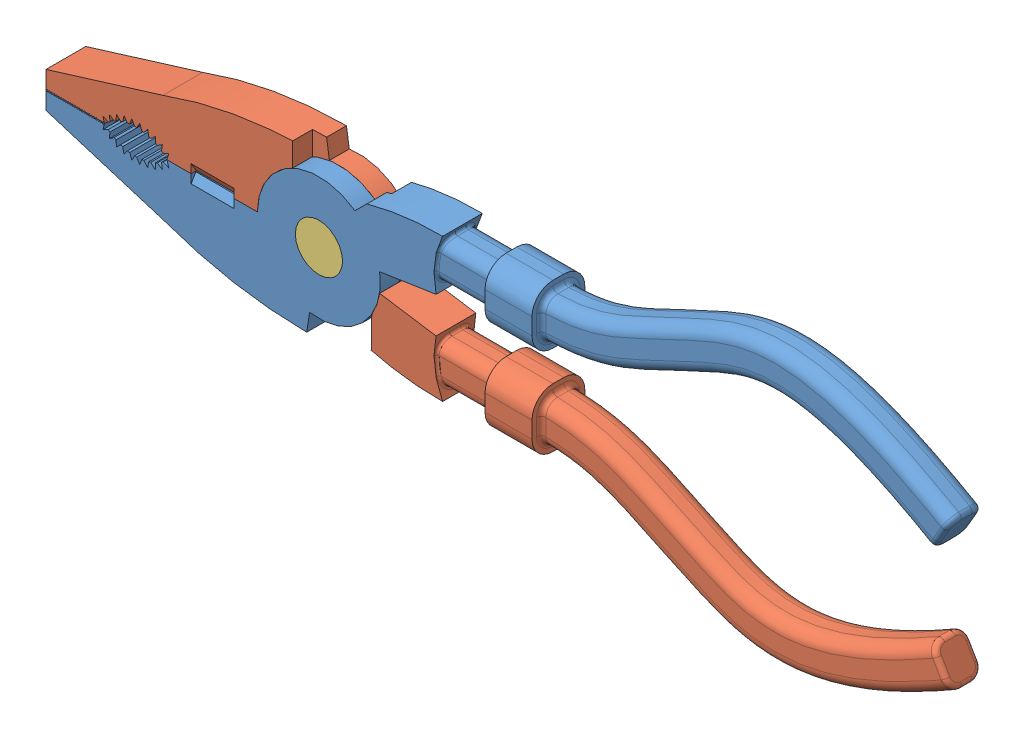
SolidWorks assembly plier, configuration Default. Lengths in mm.
Overall size (1929.21 585.48 113).
3 component instances, 3 part files, 5 mates.
Components (placement in the parent):
- pilershalf2-1: pilershalf2 [Default] at (204.7988 1257.5284 1755.4345) size (1929.21 462.74 113)
- pilershalf-1: pilershalf [Default] at (204.7988 1257.5284 1755.4345) size (1929.21 462.74 113)
- forpiler-1: forpiler [Default] at (204.7988 1257.5284 1712.9345) size (100.75 100.75 85)
Mates (geometry in assembly coordinates):
- Concentric1: concentric aligned: cylinder of pilershalf2-1 through (204.7988 1257.5284 1712.9345) axis (0 0 1) radius 50.375; cylinder of pilershalf-1 through (204.7988 1257.5284 1712.9345) axis (0 0 1) radius 50.375
- Coincident7: coincident aligned: plane of pilershalf2-1 through (204.7988 1257.5284 1797.9345) normal (0 0 1); plane of pilershalf-1 through (204.7988 1257.5284 1797.9345) normal (0 0 1)
- LimitAngle1: limit planar angle = 0 rad anti-aligned: line of pilershalf-1 through (-68.2908 1258.9175 1787.9345) axis (1 0 0); line of pilershalf2-1 through (23.1397 1238.8189 1797.9345) axis (-1 0 0)
- Concentric2: concentric anti-aligned: cylinder of pilershalf2-1 through (204.7988 1257.5284 1712.9345) axis (0 0 1) radius 50.375; cylinder of forpiler-1 through (204.7988 1257.5284 1797.9345) axis (0 0 -1) radius 50.375
- Coincident8: coincident aligned: plane of pilershalf2-1 through (204.7988 1257.5284 1797.9345) normal (0 0 1); plane of forpiler-1 through (204.7988 1257.5284 1797.9345) normal (0 0 1)
